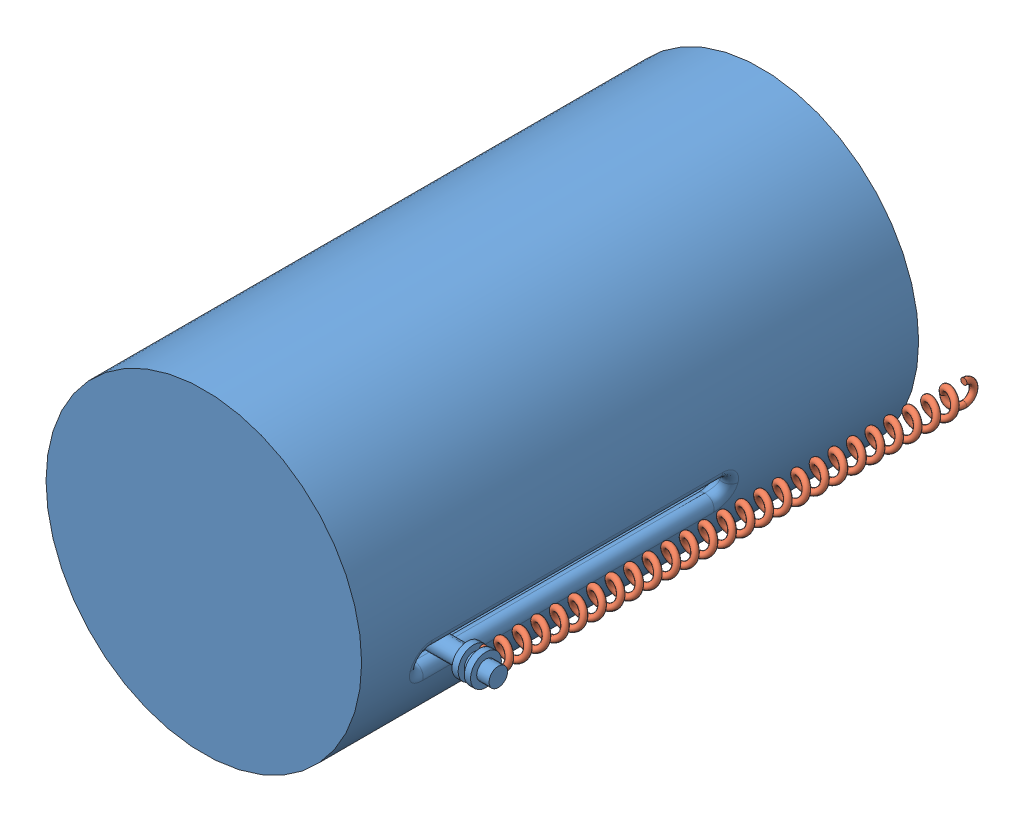
SolidWorks assembly spring assembly to the cylinder_11.06pm, configuration Default. Lengths in mm.
Overall size (66 51 94.91).
3 component instances, 2 part files, 5 mates.
Components (placement in the parent):
- bottom part-1: bottom part [Default] at (16.4612 51.9827 29.7161) size (66 51 90)
- spring-1: spring [Default] at (46.4612 46.4653 103.5318) x (0 0.999939 -0.011022) z (-1 0 0) size (5.47 82.4 5.47)
- spring-3: spring [Default] at (-13.5388 46.4838 103.5317) x (0 -1 -0.000509) z (1 0 0) size (5.47 82.4 5.47)
Mates (geometry in assembly coordinates):
- Concentric1: concentric: cylinder of bottom part-1 through (-16.5388 46.483 105.1317) axis (1 0 0) radius 1.5; circle of spring-1
- Concentric2: concentric: circle of bottom part-1; circle of spring-1
- Coincident1: coincident: plane of bottom part-1 through (46.4612 46.483 105.1317) normal (-1 0 0); circle of spring-1
- Concentric4: concentric: cylinder of bottom part-1 through (-16.5388 46.483 105.1317) axis (1 0 0) radius 1.5; circle of spring-3
- Coincident2: coincident: plane of bottom part-1 through (-13.5388 46.483 105.1317) normal (1 0 0); circle of spring-3
